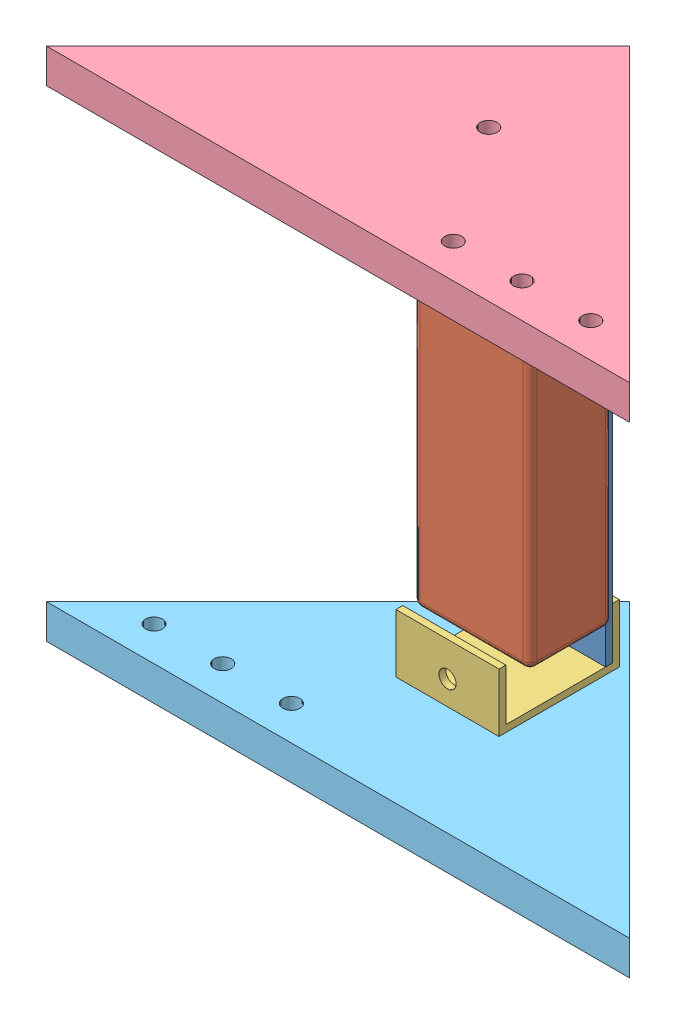
SolidWorks assembly battery_setup, configuration Default. Lengths in mm.
Overall size (169.71 150 169.71).
6 component instances, 5 part files, 15 mates.
Components (placement in the parent):
- battery_mount-1: battery_mount [Default] at (43.7581 58.3459 103.4763) size (30 126 2)
- Turnigy_2200mAh_3S_20C_Lipo_Pack-1: Turnigy_2200mAh_3S_20C_Lipo_Pack [Valor predeterminado] at (43.7581 58.3459 129.4763) x (0 1 0) z (0 0 -1) size (103 34 26)
- battery_clamp-1: battery_clamp [Default] at (58.7581 123.3459 101.4763) x (0 -1 0) z (-1 0 0) size (17 35 30)
- battery_clamp-2: battery_clamp [Default] at (28.7581 -6.6541 101.4763) x (0 1 0) z (1 0 0) size (17 35 30)
- side_frame-2: side_frame [Default] at (43.7581 123.3459 83.4763) x (0 1 0) z (0.707107 0 -0.707107) size (10 120 120)
- side_frame - Copy-1: side_frame - Copy [Default] at (43.7581 -16.6541 83.4763) x (0 1 0) z (0.707107 0 -0.707107) size (10 120 120)
Mates (geometry in assembly coordinates):
- Concentric1: concentric anti-aligned: cylinder of battery_mount-1 through (43.7581 58.3459 105.4763) axis (0 0 -1) radius 2.5; cylinder of Turnigy_2200mAh_3S_20C_Lipo_Pack-1 through (43.7581 58.3459 103.4763) axis (0 0 1) radius 2.5
- Parallel1: parallel aligned: plane of battery_mount-1 through (58.7581 121.3459 105.4763) normal (1 0 0); plane of Turnigy_2200mAh_3S_20C_Lipo_Pack-1 through (60.7581 6.8459 105.4763) normal (1 0 0)
- Coincident2: coincident aligned: plane of battery_mount-1 through (43.7581 58.3459 103.4763) normal (0 0 -1); plane of Turnigy_2200mAh_3S_20C_Lipo_Pack-1 through (43.7581 58.3459 103.4763) normal (0 0 -1)
- Concentric2: concentric anti-aligned: cylinder of battery_mount-1 through (43.7581 116.3459 105.4763) axis (0 0 -1) radius 2.5; cylinder of battery_clamp-1 through (43.7581 116.3459 93.4763) axis (0 0 1) radius 2.5
- Coincident3: coincident aligned: plane of battery_mount-1 through (58.7581 121.3459 105.4763) normal (1 0 0); plane of battery_clamp-1 through (58.7581 123.3459 101.4763) normal (1 0 0)
- Coincident5: coincident anti-aligned: plane of battery_mount-1 through (43.7581 58.3459 103.4763) normal (0 0 -1); plane of battery_clamp-1 through (28.7581 121.3459 103.4763) normal (0 0 1)
- Concentric3: concentric anti-aligned: cylinder of battery_mount-1 through (43.7581 0.3459 105.4763) axis (0 0 -1) radius 2.5; cylinder of battery_clamp-2 through (43.7581 0.3459 93.4763) axis (0 0 1) radius 2.5
- Coincident6: coincident aligned: plane of battery_mount-1 through (28.7581 121.3459 105.4763) normal (-1 0 0); plane of battery_clamp-2 through (28.7581 -6.6541 101.4763) normal (-1 0 0)
- Coincident7: coincident anti-aligned: plane of battery_mount-1 through (43.7581 58.3459 103.4763) normal (0 0 -1); plane of battery_clamp-2 through (58.7581 -4.6541 103.4763) normal (0 0 1)
- Coincident14: coincident anti-aligned: plane of battery_clamp-1 through (28.7581 123.3459 101.4763) normal (0 1 0); plane of side_frame-2 through (43.7581 123.3459 83.4763) normal (0 -1 0)
- Concentric5: concentric anti-aligned: cylinder of battery_clamp-1 through (43.7581 131.3459 124.4763) axis (0 -1 0) radius 2.5; cylinder of side_frame-2 through (43.7581 123.3459 124.4763) axis (0 1 0) radius 2.5
- Parallel7: parallel aligned: plane of battery_mount-1 through (43.7581 58.3459 105.4763) normal (0 0 1); plane of side_frame-2 through (-41.0947 133.3459 168.3291) normal (0 0 1)
- Coincident15: coincident anti-aligned: plane of battery_clamp-2 through (58.7581 -6.6541 101.4763) normal (0 -1 0); plane of side_frame - Copy-1 through (43.7581 -6.6541 83.4763) normal (0 1 0)
- Concentric6: concentric aligned: cylinder of battery_clamp-2 through (43.7581 -14.6541 124.4763) axis (0 1 0) radius 2.5; cylinder of side_frame - Copy-1 through (43.7581 -16.6541 124.4763) axis (0 1 0) radius 2.5
- Parallel8: parallel aligned: plane of battery_clamp-2 through (28.7581 -6.6541 136.4763) normal (0 0 1); plane of side_frame - Copy-1 through (-41.0947 -6.6541 168.3291) normal (0 0 1)
